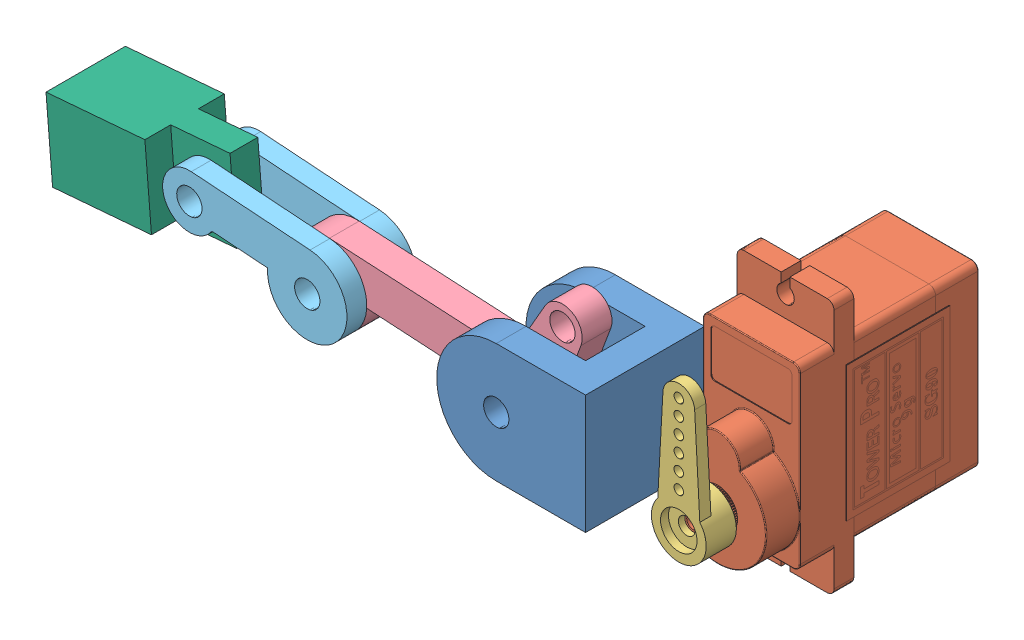
SolidWorks assembly Assem2, configuration Default. Lengths in mm.
Overall size (86.49 32.1 31.75).
7 component instances, 6 part files, 12 mates.
Components (placement in the parent):
- Finger2Base-1: Finger2Base [Default] at (-5.5059 12.9049 15.8316) x (0 1 0) z (0 0 1) size (15 18.75 15)
- SG90 - Micro Servo 9g - Tower Pro.1-1: SG90 - Micro Servo 9g - Tower Pro.1 [Peça] at (8.1123 16.6549 2.2316) x (0 1 0) z (1 0 0) size (32.1 29.95 12.4)
- SG90 - Micro Servo 9g - Tower Pro.2-1: SG90 - Micro Servo 9g - Tower Pro.2 [Peça] at (8.1123 11.5049 23.3316) x (0 -1 0) z (-1 0 0) size (19.5 3.8 6.9)
- Joint1-1: Joint1 [Default] at (-39.9407 12.6434 19.5816) x (-0.059418 -0.998233 0) z (0 0 -1) size (19.25 36.5 3.75)
- Joint2-1: Joint2 [Default] at (-54.7878 15.3276 22.0816) x (-0.070884 -0.997485 0) z (0 0 -1) size (10 23.38 2.5)
- Joint2-2: Joint2 [Default] at (-54.7878 15.3276 15.8316) x (-0.070884 -0.997485 0) z (0 0 -1) size (10 23.38 2.5)
- Joint3-1: Joint3 [Default] at (-65.116 9.4504 17.7566) x (0.996552 0.082972 0) z (0 0 1) size (20 10 10)
Mates (geometry in assembly coordinates):
- Concentric1: concentric aligned: cylinder of SG90 - Micro Servo 9g - Tower Pro.1-1 through (8.1123 11.5049 21.5316) axis (0 0 1) radius 0.8; cylinder of SG90 - Micro Servo 9g - Tower Pro.2-1 through (8.1123 11.5049 23.3316) axis (0 0 1) radius 1.05
- Coincident1: coincident anti-aligned: plane of SG90 - Micro Servo 9g - Tower Pro.1-1 through (8.1123 11.5049 21.5316) normal (0 0 1); plane of SG90 - Micro Servo 9g - Tower Pro.2-1 through (8.1123 11.5049 21.5316) normal (0 0 -1)
- Coincident2: coincident aligned: plane of Finger2Base-1 through (-5.5059 12.9049 23.3316) normal (0 0 1); plane of SG90 - Micro Servo 9g - Tower Pro.2-1 through (8.1123 11.5049 23.3316) normal (0 0 1)
- Coincident3: coincident aligned: plane of Finger2Base-1 through (-3.6309 5.4049 23.3316) normal (0 -1 0); plane of SG90 - Micro Servo 9g - Tower Pro.1-1 through (2.8623 5.4049 62.2763) normal (0 -1 0)
- Concentric3: concentric aligned: cylinder of Finger2Base-1 through (-14.8809 12.9049 8.975) axis (0 0 1) radius 1.6; cylinder of Joint1-1 through (-14.8809 12.9049 15.8316) axis (0 0 1) radius 1.6
- Coincident4: coincident anti-aligned: plane of Finger2Base-1 through (-22.3809 5.4049 19.5816) normal (0 0 -1); plane of Joint1-1 through (-39.9407 12.6434 19.5816) normal (0 0 1)
- Concentric4: concentric aligned: cylinder of Joint1-1 through (-39.9407 12.6434 15.8316) axis (0 0 1) radius 1.6; cylinder of Joint2-1 through (-39.9407 12.6434 19.5816) axis (0 0 1) radius 1.6
- Coincident6: coincident anti-aligned: plane of Joint1-1 through (-39.9407 12.6434 19.5816) normal (0 0 1); plane of Joint2-1 through (-54.7878 15.3276 19.5816) normal (0 0 -1)
- Concentric6: concentric aligned: cylinder of Joint2-1 through (-39.9407 12.6434 19.5816) axis (0 0 1) radius 5; cylinder of Joint2-2 through (-39.9407 12.6434 13.3316) axis (0 0 1) radius 5
- Coincident7: coincident anti-aligned: plane of Joint1-1 through (-39.9407 12.6434 15.8316) normal (0 0 -1); plane of Joint2-2 through (-54.7878 15.3276 15.8316) normal (0 0 1)
- Coincident8: coincident aligned: cylinder of Joint2-1 through (-54.7878 15.3276 19.5816) axis (0 0 1) radius 1.6; circle of Joint3-1
- Distance1: distance = 0.075 mm anti-aligned: plane of Joint3-1 through (-65.9458 19.4159 19.5066) normal (0 0 1); plane of Joint2-1 through (-54.7878 15.3276 19.5816) normal (0 0 -1)
